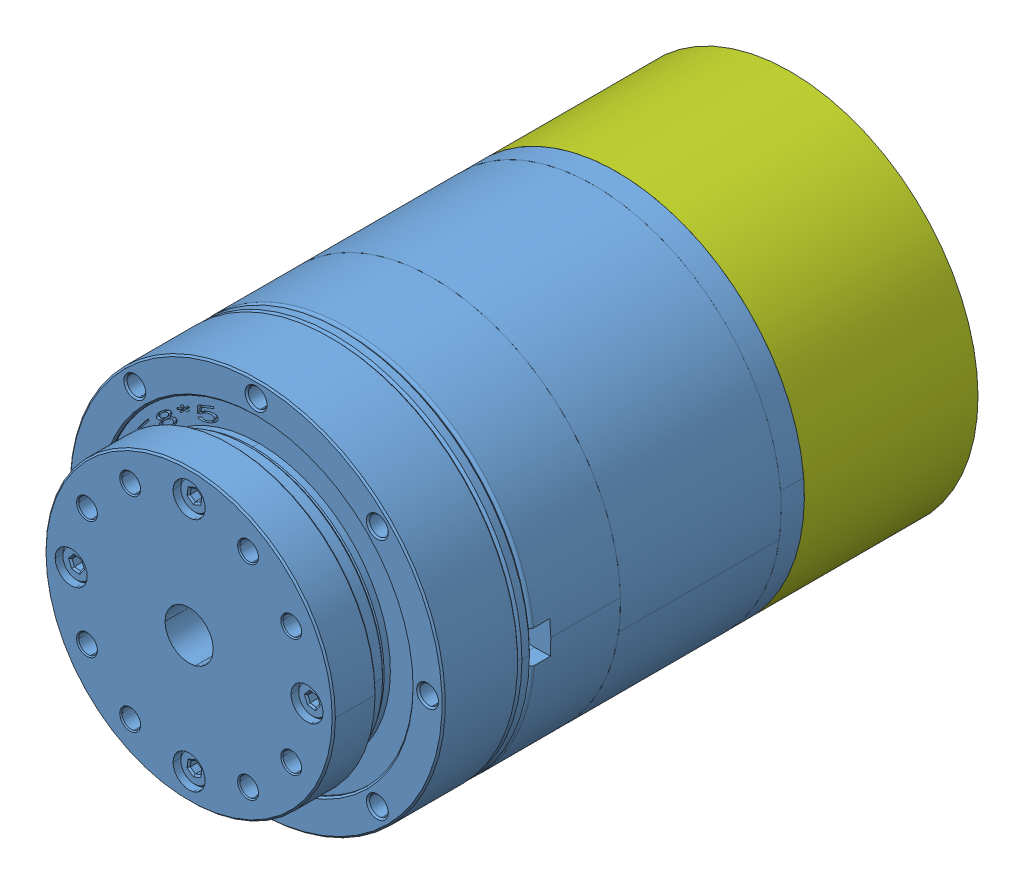
SolidWorks assembly HCA-20, configuration 默认. Lengths in mm.
Overall size (98.88 98.88 112.21).
10 component instances, 7 part files, 0 mates.
Components (placement in the parent):
- HCA-20.STEP-1: HCA-20.STEP [默认] at origin size (98.88 98.88 112.21)
  - YF14.STEP.STEP-1: YF14.STEP.STEP [默认] at (-228.6784 -64.8113 45.55) size (70 70 91.3)
  - ________ - __________-14.STEP-1: ________ - __________-14.STEP [默认] at (-261.9173 -42.4852 -3.55) x (-0.796704 -0.60437 0) z (0 0 -1) size (20 20 5.05)
  - 3418____.step.STEP-1: 3418____.step.STEP [默认] at (-261.9173 -42.4852 -16.65) x (0.8025 -0.596652 0) z (0.596652 0.8025 0) size (34 4.9 34)
  - ________ - __________-____-14.STEP-1: ________ - __________-____-14.STEP [默认] at (-261.9173 -42.4852 -13.15) x (0.968461 0.249167 0) z (0 0 -1) size (19.8 19.8 5)
  - 3418____.step.STEP-2: 3418____.step.STEP [默认] at (-261.9173 -42.4852 -26.25) x (-0.497426 -0.867507 0) z (0.867507 -0.497426 0) size (34 4.9 34)
  - __________B__V2.2 - ____.STEP-1: __________B__V2.2 - ____.STEP [默认] at (-261.9173 -42.4852 -24.6) x (-0.211216 0.977439 0) z (0 0 -1) size (53.8 51.9 3.5)
  - __________B__V2.2 - ____.STEP-2: __________B__V2.2 - ____.STEP [默认] at (-261.9173 -42.4852 -34.2) x (-0.211216 0.977439 0) z (0 0 -1) size (53.8 51.9 3.5)
  - __________.STEP-1: __________.STEP [默认] at (-232.571 -71.2286 -40.2901) x (0.671632 -0.740885 0) z (0 0 -1) size (55 55 14.71)
  - ____ - 14 - ____.STEP-1: ____ - 14 - ____.STEP [默认] at (-261.9173 -42.4852 -47.4) x (-0.671638 0.740879 0) z (0 0 1) size (70 70 32.4)
